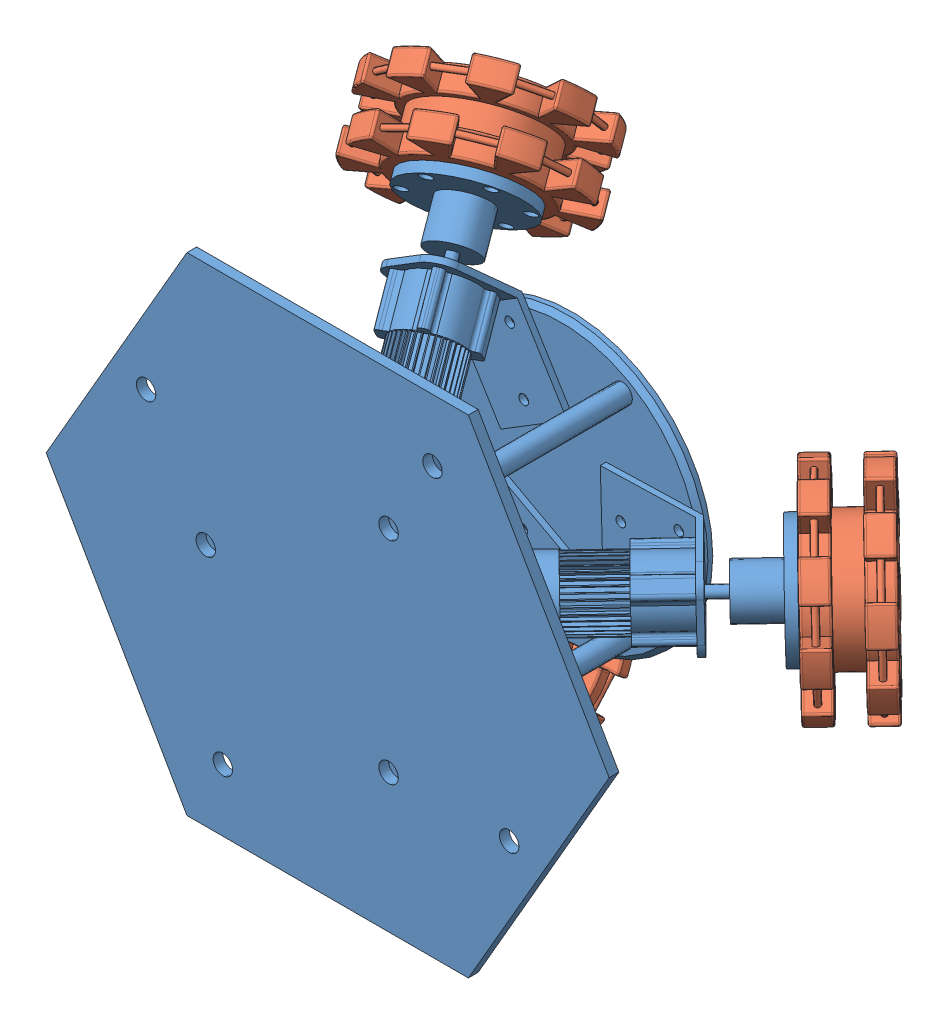
SolidWorks assembly AssemBallbot_sanpoomGOD, configuration Default. Lengths in mm.
Overall size (317.03 336.57 267.59).
5 component instances, 2 part files, 0 mates.
Components (placement in the parent):
- AssemBallbot_sanpoomGOD.step-1: AssemBallbot_sanpoomGOD.step [Default] at origin size (317.03 336.57 202.24)
  - BallBalancingRobot_Frame.step-1: BallBalancingRobot_Frame.step [Default] at (-81.9116 71.2492 -21.9014) size (288.68 250 150.17)
  - omniwhee.step-1: omniwhee.step [Default] at (-142.1958 -37.8168 -164.8824) x (0.941899 -0.221898 -0.252166) z (0.335896 0.622233 0.707107) size (100 99.99 36.01)
  - omniwhee.step-2: omniwhee.step [Default] at (42.6845 73.5746 -164.8824) x (0.707396 -0.020205 0.706529) z (-0.706818 -0.020222 0.707107) size (100 99.99 36.01)
  - omniwhee.step-3: omniwhee.step [Default] at (-146.2234 177.9899 -164.8824) x (0.928664 0.240452 -0.282428) z (0.370921 -0.602011 0.707107) size (100 99.99 36.01)
